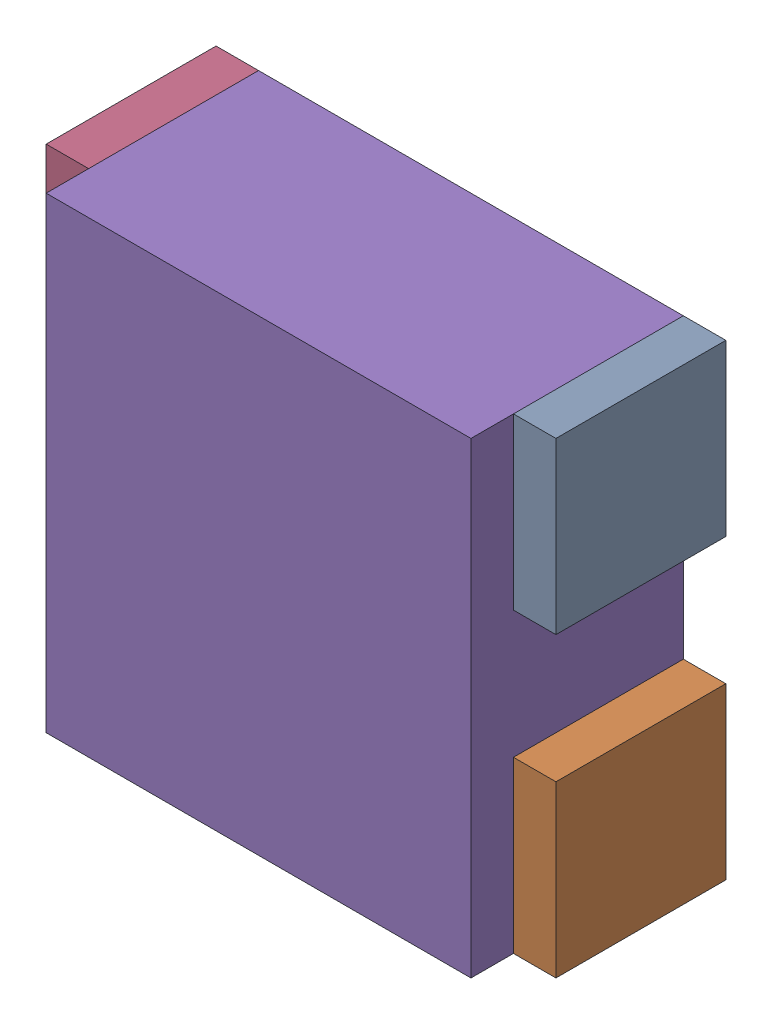
SolidWorks assembly RN18, configuration Default. Lengths in mm.
Overall size (1.2 1.1 0.5).
10 component instances, 2 part files, 0 mates.
Components (placement in the parent):
- 791587232-1: 791587232 [Default] at (119 71.425 0) size (0.1 0.4 0.4)
  - Extruded_10-1: Extruded_10 [Default] at origin size (0.1 0.4 0.4)
- 791587232-2: 791587232 [Default] at (119 70.725 0) size (0.1 0.4 0.4)
  - Extruded_10-1: Extruded_10 [Default] at origin size (0.1 0.4 0.4)
- 791587232-3: 791587232 [Default] at (117.9 70.725 0) size (0.1 0.4 0.4)
  - Extruded_10-1: Extruded_10 [Default] at origin size (0.1 0.4 0.4)
- 791587232-4: 791587232 [Default] at (117.9 71.425 0) size (0.1 0.4 0.4)
  - Extruded_10-1: Extruded_10 [Default] at origin size (0.1 0.4 0.4)
- 836749552-1: 836749552 [Default] at (118.45 71.075 0) size (1 1.1 0.5)
  - Extruded_11-1: Extruded_11 [Default] at origin size (1 1.1 0.5)
